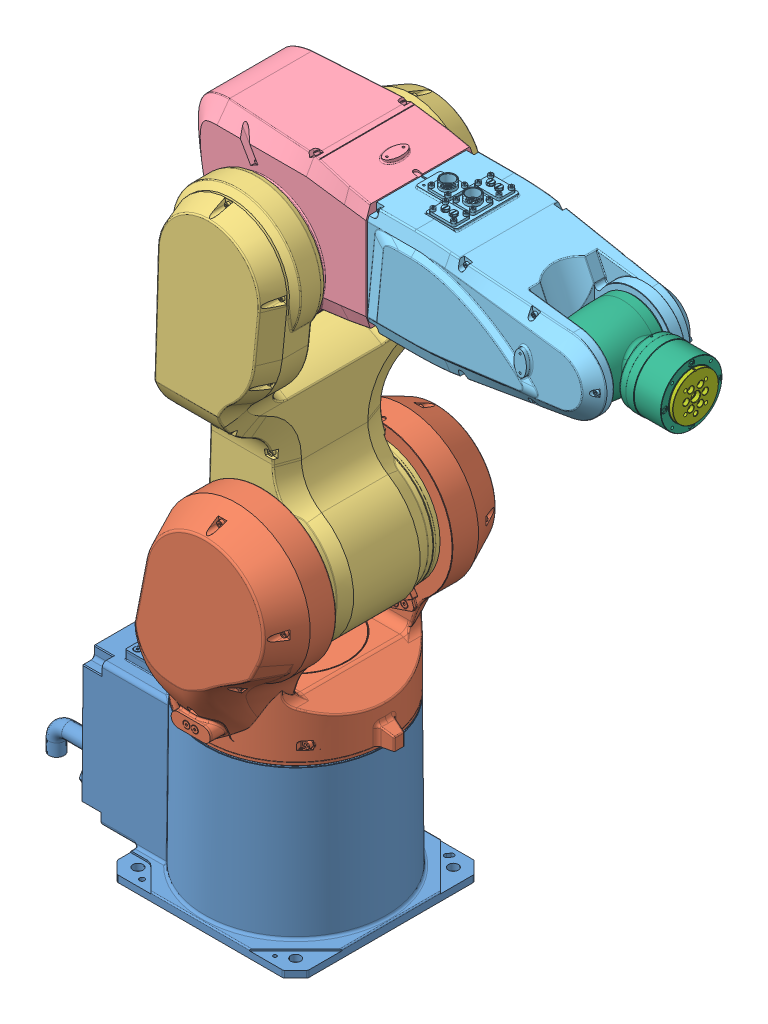
SolidWorks assembly P7B-700简化模型(可拖拽), configuration 默认. Lengths in mm.
Overall size (754 821.75 324.15).
7 component instances, 7 part files, 18 mates.
Components (placement in the parent):
- GBT-P7B-base-2: GBT-P7B-base [默认] at origin size (387 201.5 230.18)
- GBT-P7B-shoulder-2: GBT-P7B-shoulder [默认] at (0 194 0) size (233 264.18 324.15)
- GBT-P7B-700-large_arm-2: GBT-P7B-700-large_arm [默认] at (30 365 0) size (160.62 497.5 271.5)
- GBT-P7B-elbow-2: GBT-P7B-elbow [默认] at (30 705 0) size (223.57 189.32 158.51)
- GBT-P7B-700-little_arm-2: GBT-P7B-700-little_arm [默认] at (151.5 740 0) size (277.17 143.71 150.77)
- GBT-P7B-wrist-2: GBT-P7B-wrist [默认] at (380 740 0) size (140.37 85 79.5)
- GBT-P7B-flange-2: GBT-P7B-flange [默认] at (469 740 0) x (1 0 0) z (0 -1 0) size (18 55 55)
Mates (geometry in assembly coordinates):
- 同心1: concentric anti-aligned: cylinder of GBT-P7B-base-1-2 through (0 405.8183 0) axis (0 -1 0) radius 71; cylinder of GBT-P7B-shoulder-2 through (0 194 0) axis (0 1 0) radius 108
- 重合1: coincident anti-aligned: plane of GBT-P7B-base-1-2 through (0 190 0) normal (0 1 0); plane of GBT-P7B-shoulder-2 through (0 190 0) normal (0 -1 0)
- 重合2: coincident aligned: plane of GBT-P7B-base-2 through (0 0 0) normal (0 0 1); plane of GBT-P7B-shoulder-2 through (0 194 0) normal (0 0 1)
- 同心2: concentric aligned: cylinder of GBT-P7B-large_arm-2 through (30 365 -294.8036) axis (0 0 1) radius 74; cylinder of GBT-P7B-shoulder-2 through (30 365 -80) axis (0 0 1) radius 74
- 重合3: coincident aligned: plane of GBT-P7B-shoulder-2 through (0 194 0) normal (0 0 1); plane of GBT-P7B-large_arm-2 through (30 365 0) normal (0 0 1)
- 平行1: parallel aligned: plane of GBT-P7B-shoulder-2 through (0 194 0) normal (1 0 0); plane of GBT-P7B-large_arm-2 through (30 365 0) normal (1 0 0)
- 同心3: concentric anti-aligned: cylinder of GBT-P7B-large_arm-2 through (30 705 -85.5) axis (0 0 1) radius 57.5; cylinder of GBT-P7B-elbow-2 through (30 705 -67) axis (0 0 -1) radius 57.5
- 重合4: coincident aligned: plane of GBT-P7B-large_arm-2 through (30 365 0) normal (0 0 1); plane of GBT-P7B-elbow-2 through (30 705 0) normal (0 0 1)
- 平行2: parallel aligned: plane of GBT-P7B-large_arm-2 through (30 365 0) normal (1 0 0); plane of GBT-P7B-elbow-2 through (30 815 0) normal (1 0 0)
- 同心4: concentric aligned: cylinder of GBT-P7B-elbow-2 through (137.5 740 0) axis (-1 0 0) radius 49.5; cylinder of GBT-P7B-700-little_arm-2 through (223.5 740 0) axis (-1 0 0) radius 49.5
- 重合5: coincident anti-aligned: plane of GBT-P7B-elbow-2 through (153.5 740 0) normal (1 0 0); plane of GBT-P7B-700-little_arm-2 through (153.5 740 0) normal (-1 0 0)
- 重合6: coincident aligned: plane of GBT-P7B-elbow-2 through (30 815 0) normal (0 0 1); plane of GBT-P7B-little_arm-2 through (221.5 850 0) normal (0 0 1)
- 同心5: concentric anti-aligned: cylinder of GBT-P7B-little_arm-2 through (450 740 -74.7776) axis (0 0 -1) radius 29.5; cylinder of GBT-P7B-wrist-2 through (450 740 -27.1377) axis (0 0 1) radius 29.5
- 重合7: coincident aligned: plane of GBT-P7B-little_arm-2 through (221.5 740 0) normal (0 0 1); plane of GBT-P7B-wrist-2 through (450 740 0) normal (0 0 1)
- 平行3: parallel aligned: plane of GBT-P7B-little_arm-2 through (221.5 850 0) normal (0 1 0); plane of GBT-P7B-wrist-2 through (450 850 0) normal (0 1 0)
- 同心6: concentric anti-aligned: cylinder of GBT-P7B-wrist-2 through (539 740 0) axis (1 0 0) radius 21; cylinder of GBT-P7B-flange-2 through (539 740 0) axis (-1 0 0) radius 21
- 重合8: coincident anti-aligned: plane of GBT-P7B-wrist-2 through (539 740 -13.8) normal (1 0 0); plane of GBT-P7B-flange-2 through (539 740 5.5) normal (-1 0 0)
- 重合9: coincident aligned: plane of GBT-P7B-wrist-2 through (450 850 0) normal (0 0 1); plane of GBT-P7B-flange-2 through (539 850 0) normal (0 0 1)
